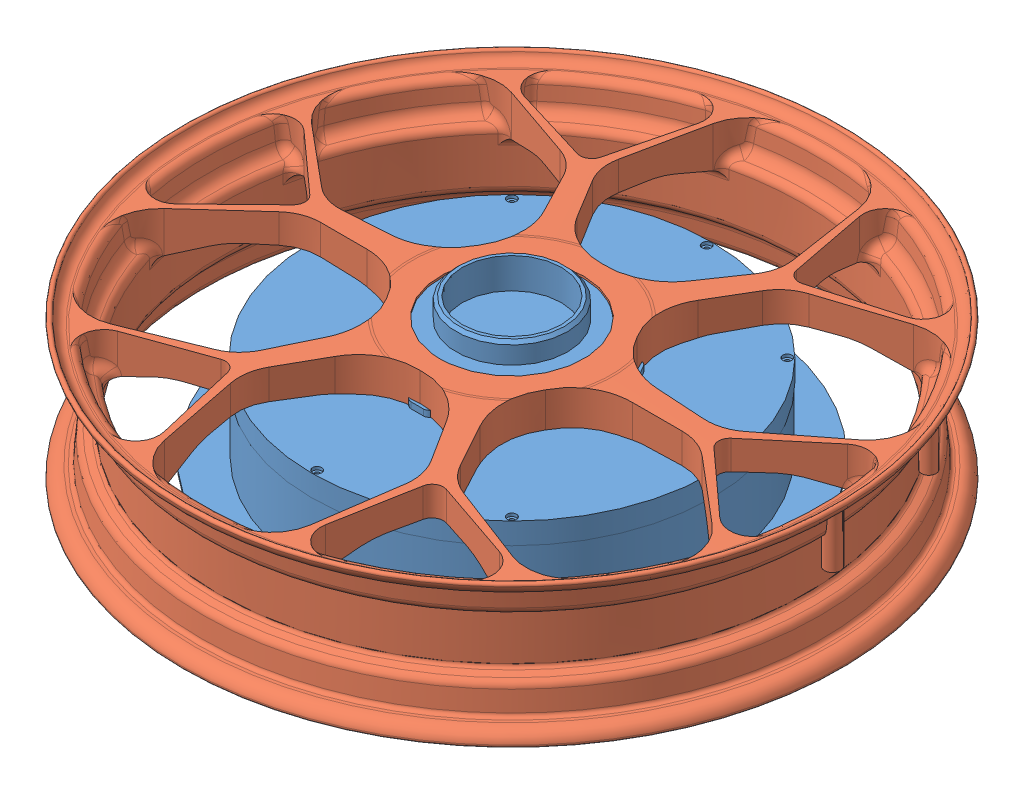
SolidWorks assembly MisubaDiskWheel, configuration Default. Lengths in mm.
Overall size (431.57 108 431.57).
2 component instances, 2 part files, 2 mates.
Components (placement in the parent):
- Motor Mitsuba M2096 D-III-1: Motor Mitsuba M2096 D-III [Default] at origin size (310 108 310)
- rimmachined13-1: rimmachined13 [Default] at (0 -8.3 0) x (0 1 0) z (0 0 1) size (93.59 431.57 431.57)
Mates (geometry in assembly coordinates):
- Concentric1: concentric: cylinder of Motor Mitsuba M2096 D-III-1 through (0 14 0) axis (0 -1 0) radius 47; cylinder of rimmachined13-1 through (0 0.8 0) axis (0 1 0) radius 47
- Coincident1: coincident anti-aligned: plane of Motor Mitsuba M2096 D-III-1 through (0 14 0) normal (0 1 0); plane of rimmachined13-1 through (-40 14 0) normal (0 -1 0)
